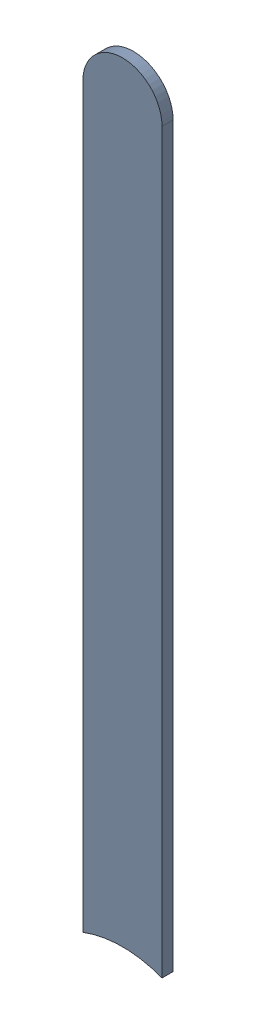
SolidWorks assembly Track (19.2mm,46.4mm)(19.2mm,49.1mm) on Top Layer, configuration Predeterminado. Lengths in mm.
Overall size (0.25 2.49 0.04).
2 component instances, 1 part files, 0 mates.
Components (placement in the parent):
- Track (19.2mm,46.4mm)(19.2mm,49.1mm) on Top Layer-1-1: Track (19.2mm,46.4mm)(19.2mm,49.1mm) on Top Layer-1 [Predeterminado] at (-68.317 -44.187 -0.0457) size (0.25 2.49 0.04)
  - Track (19.2mm,46.4mm)(19.2mm,49.1mm) on Top Layer-Part-1-1: Track (19.2mm,46.4mm)(19.2mm,49.1mm) on Top Layer-Part-1 [Predeterminado] at origin size (0.25 2.49 0.04)
